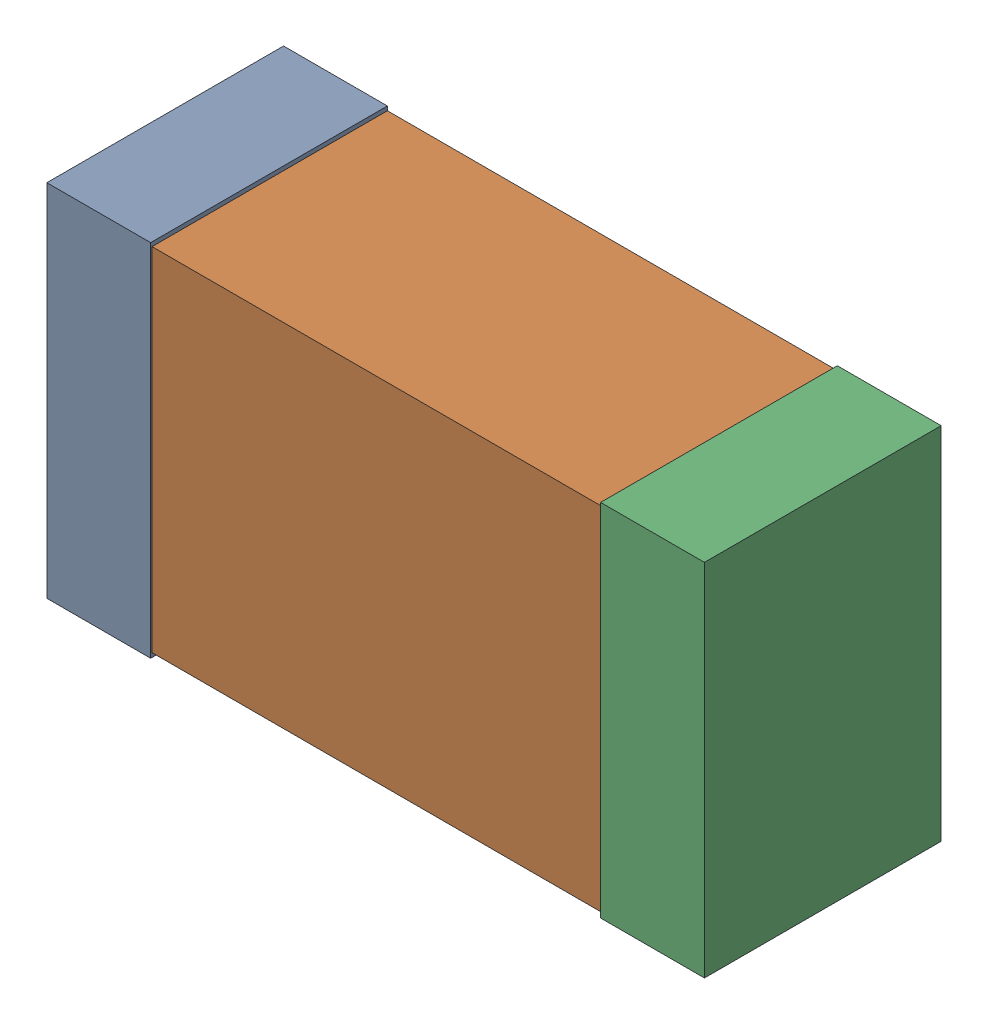
SolidWorks assembly C14_Motor_6Kanaloa_v2.0.0_Motor, configuration Default. Lengths in mm.
Overall size (2.38 1.3 0.85).
6 component instances, 2 part files, 0 mates.
Components (placement in the parent):
- 352877648-1: 352877648 [Default] at (34.01 138.43 0) size (0.38 1.3 0.85)
  - Extruded_14-1: Extruded_14 [Default] at origin size (0.38 1.3 0.85)
- 352877392-1: 352877392 [Default] at (35.01 138.43 0) size (2.2 1.27 0.85)
  - Extruded_15-1: Extruded_15 [Default] at origin size (2.2 1.27 0.85)
- 352877648-2: 352877648 [Default] at (36.01 138.43 0) size (0.38 1.3 0.85)
  - Extruded_14-1: Extruded_14 [Default] at origin size (0.38 1.3 0.85)
